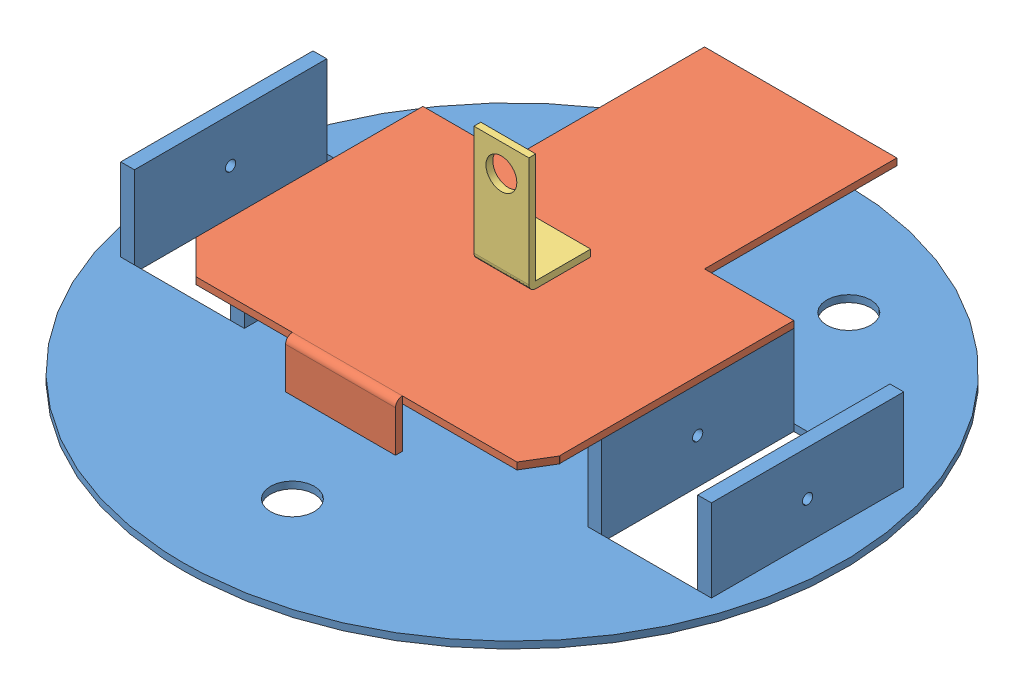
SolidWorks assembly Bare_body, configuration Default. Lengths in mm.
Overall size (304.8 98.43 304.8).
3 component instances, 3 part files, 4 mates.
Components (placement in the parent):
- Frame-1: Frame [Default] at (-17.1359 8.2342 3.4482) size (304.8 41.27 304.8)
- lvl2-1: lvl2 [Default] at (-17.1359 49.5092 12.9732) size (171.54 22.23 212.73)
- bracket_arm-1: bracket_arm [Default] at (-16.4827 81.2592 9.1073) x (-1 0 0) z (0 0 -1) size (25.4 53.98 28.58)
Mates (geometry in assembly coordinates):
- Coincident1: coincident anti-aligned: plane of Frame-1 through (-102.8609 49.5092 47.8982) normal (0 1 0); plane of lvl2-1 through (68.5891 49.5092 -41.0018) normal (0 -1 0)
- Coincident2: coincident anti-aligned: line of Frame-1 through (68.5891 49.5092 -41.0018) axis (0 0 1); line of lvl2-1 through (68.5891 49.5092 66.9482) axis (0 0 -1)
- Coincident3: coincident aligned: line of Frame-1 through (68.5891 49.5092 -41.0018) axis (0 -1 0); line of lvl2-1 through (68.5891 52.6842 -41.0018) axis (0 -1 0)
- Coincident4: coincident anti-aligned: plane of lvl2-1 through (68.5891 52.6842 -41.0018) normal (0 1 0); plane of bracket_arm-1 through (-3.7827 52.6842 5.9323) normal (0 -1 0)
